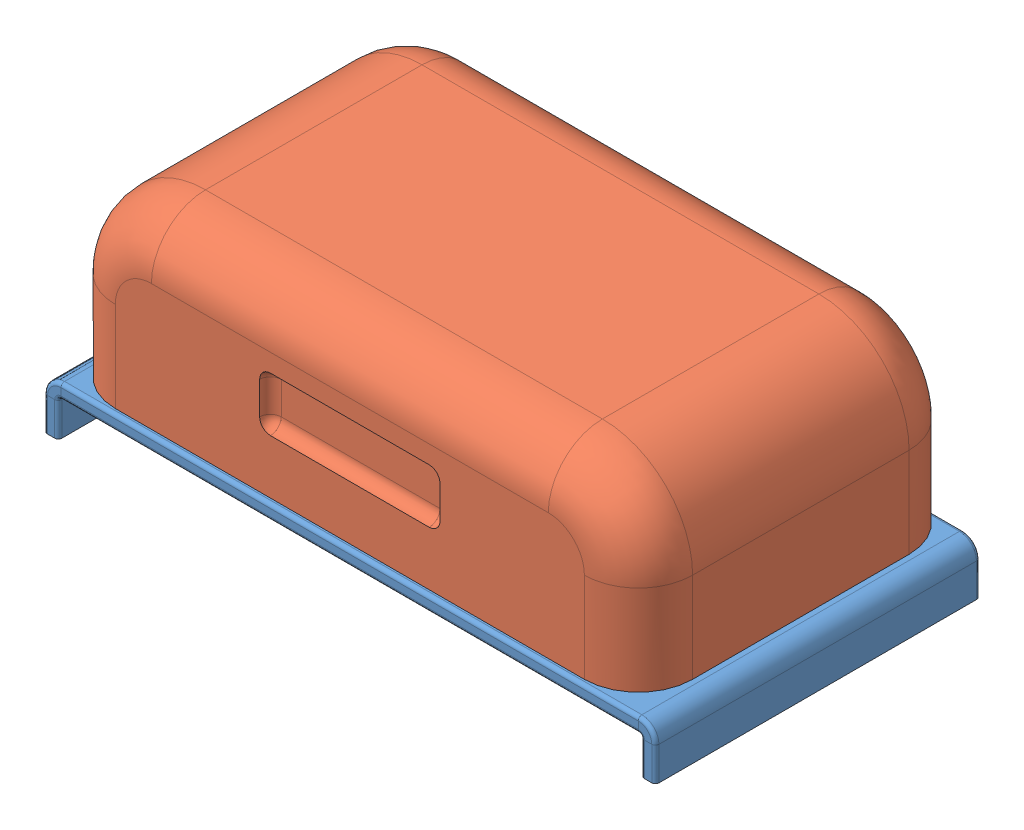
SolidWorks assembly assemblage 3mm, configuration Défaut. Lengths in mm.
Overall size (169.47 65.36 90.16).
2 component instances, 2 part files, 0 mates.
Components (placement in the parent):
- base tôle 3mm-1: base tôle 3mm [Défaut] at (24.9881 -24.1046 16.8266) size (169.47 18 90)
- couvercle 3mm-1: couvercle 3mm [Défaut] at (-37.358 -18.748 23.5502) size (160 50 90)
